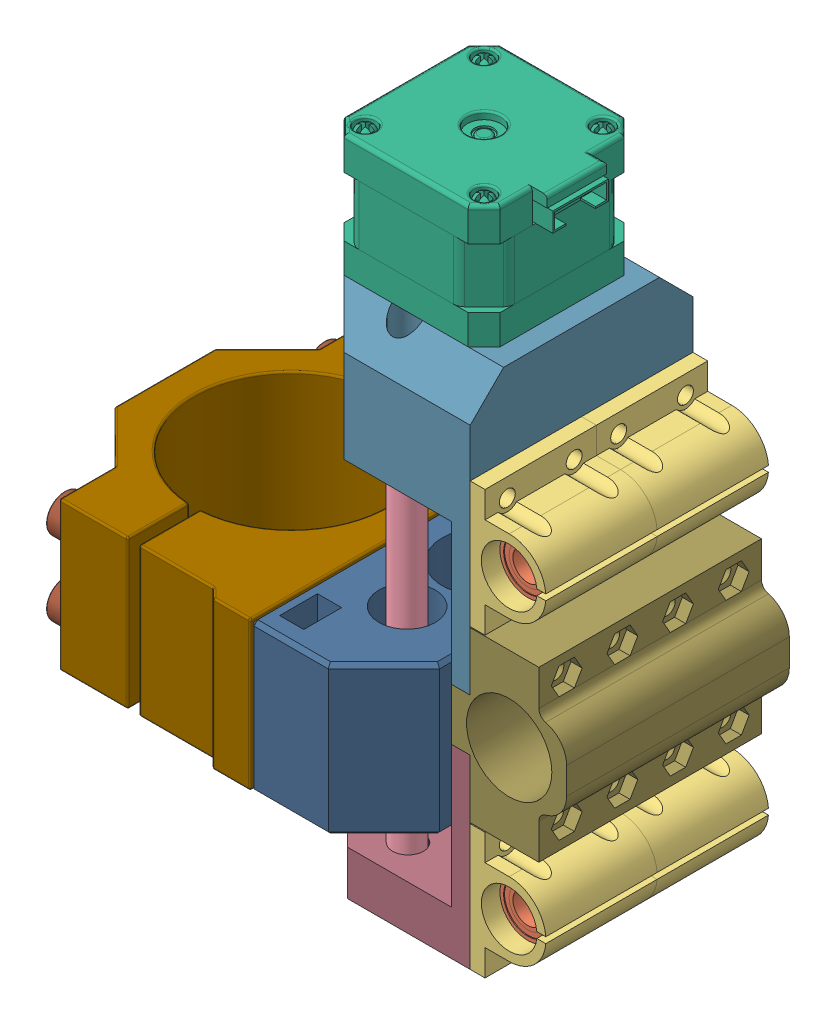
SolidWorks assembly X-carriage, configuration Default. Lengths in mm.
Overall size (138.25 171.1 90).
29 component instances, 15 part files, 0 mates.
Components (placement in the parent):
- TR8_lead_screw-1: TR8_lead_screw [Default] at (0 0 3.5) x (-1 0 0) z (0 0 1) size (22 22 16.4)
- LM8_20mm-1: LM8_20mm [Default] at (0 40 -15) size (15 15 20)
- LM8_20mm_housing-1: LM8_20mm_housing [Default] at (0 40 -15) x (0 1 0) z (1 0 0) size (34 30 20.37)
- LM8_20mm-3: LM8_20mm [Default] at (0 40 15) size (15 15 20)
- LM8_20mm_housing-2: LM8_20mm_housing [Default] at (0 40 15) x (0 1 0) z (1 0 0) size (34 30 20.37)
- LM8_20mm_housing-3: LM8_20mm_housing [Default] at (0 -40 15) x (0 1 0) z (1 0 0) size (34 30 20.37)
- LM8_20mm-4: LM8_20mm [Default] at (0 -40 15) size (15 15 20)
- LM8_20mm_housing-4: LM8_20mm_housing [Default] at (0 -40 -15) x (0 1 0) z (1 0 0) size (34 30 20.37)
- LM8_20mm-5: LM8_20mm [Default] at (0 -40 -15) size (15 15 20)
- Carriage-1: Carriage [Default] x (0 0 -1) z (1 0 0) size (60 136 73) (hidden)
- 112mmx8mm_linear_guide-1: 112mmx8mm_linear_guide [Default] at (-36.75 -55 -20.75) size (8 112 8)
- 112mmx8mm_linear_guide-3: 112mmx8mm_linear_guide [Default] at (-36.75 -55 20.75) size (8 112 8)
- 688Z-1: 688Z [Default] at (-36.75 -52.5 0) size (16 5 16)
- Nema_17-1: Nema_17 [Default] at (-36.75 87 0) x (0 0 1) z (1 0 0) size (42 55.32 47)
- Coupling-1: Coupling [Default] at (-36.75 57.25 0) x (1 0 0) z (0 0 -1) size (19.94 24.5 19.46)
- 114mm_M8x2_lead_screw-2: 114mm_M8x2_lead_screw [Valor predeterminado] at (-36.75 0 0) x (1 0 0) z (0 -1 0) size (8 8 117.9)
- Spindle_assembly-1: Spindle_assembly [Default] at (-36.75 -10 0) x (0 0 1) z (-1 0 0) size (90 40 104)
  - TR8_lead_screw-1: TR8_lead_screw [Default] at (0 3.5 0) x (1 0 0) z (0 1 0) size (22 22 16.4)
  - LM8_20mm-3: LM8_20mm [Default] at (-20.75 0 0) x (1 0 0) z (0 -1 0) size (15 15 20)
  - LM8_20mm-4: LM8_20mm [Default] at (20.75 0 0) x (1 0 0) z (0 -1 0) size (15 15 20)
  - Spindle_mount-1: Spindle_mount [Default] at (0 0 52) x (1 0 0) z (0 -1 0) size (90 68 40)
  - Tool_mount-1: Tool_mount [Default] at origin size (90 40 36)
  - M6x60-1: M6x60 [Default] at (-35 10 72) x (1 0 0) z (0 -1 0) size (10 66 10)
  - M6x60-5: M6x60 [Default] at (-35 -10 72) x (1 0 0) z (0 -1 0) size (10 66 10)
  - M6x60-6: M6x60 [Default] at (35 10 72) x (1 0 0) z (0 -1 0) size (10 66 10)
  - M6x60-7: M6x60 [Default] at (35 -10 72) x (1 0 0) z (0 -1 0) size (10 66 10)
- Mid_Carriage-1: Mid_Carriage [Default] x (0 0 -1) z (1 0 0) size (60 45.5 31)
- Lower_Carriage-1: Lower_Carriage [Default] x (0 0 -1) z (1 0 0) size (60 50 47)
- Upper_Carriage-1: Upper_Carriage [Default] x (0 0 -1) z (1 0 0) size (60 72 47)
